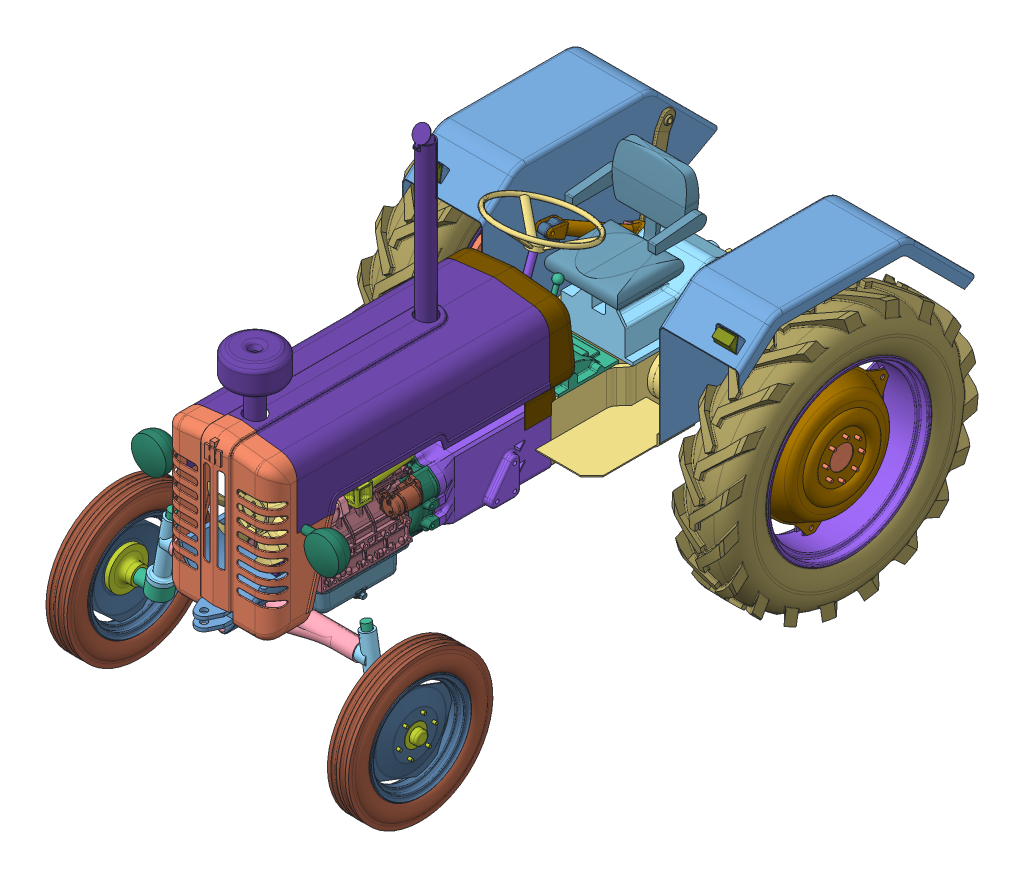
SolidWorks assembly Mc Cormik-D326, configuration Default. Lengths in mm.
Overall size (1708.06 2244.02 3061.96).
66 component instances, 48 part files, 134 mates.
Components (placement in the parent):
- Pivot Axle-1: Pivot Axle [Default] at (-85.0186 771.2904 1627.9761) x (-1 0 0) z (0 0 -1) size (392.24 270 440)
- Rear Hub-1: Rear Hub [Default] at (711.9814 589.2904 -376.0239) x (0 -0.617055 0.78692) z (-1 0 0) size (220 220 100)
- Rear Hub-2: Rear Hub [Default] at (-878.0186 589.2904 -376.0239) x (0 -0.032146 0.999483) z (1 0 0) size (220 220 100)
- Block-1: Block [Default<As Machined>] at (-263.0186 534.2904 273.9761) size (1440 380 1075)
- Coupling-1: Coupling [Default] at (-118.0186 379.2904 -199.5137) size (70 87 710)
- Liftng Block-1: Liftng Block [Default] at (-83.0186 814.2904 -51.0239) size (360 240 555)
- Transmision Cover-1: Transmision Cover [Défaut] at (-73.0186 811.2904 238.9721) size (250 361.14 270)
- Soporte del tiro-1: Soporte del tiro [Default] at (-213.0186 429.2904 -619.0239) size (315 325 60)
- Clutch Block-1: Clutch Block [Default] at (-83.0186 672.7904 708.9761) x (0 0 -1) z (1 0 0) size (619.03 793.15 344.07)
- Lift Arm-1: Lift Arm [Default] at (241.9814 982.0279 -696.6432) x (0 0.10751 -0.994204) z (1 0 0) size (387.95 79.9 190.01)
- Lift Arm-3: Lift Arm [Default] at (-408.0186 1036.5986 -195.6199) x (0 0.319024 0.947747) z (-1 0 0) size (387.95 79.9 190.01)
- Lift Pivot-1: Lift Pivot [Default] at (229.4814 914.6963 -770.8621) x (0 0.061661 -0.998097) z (1 0 0) size (72 95 40)
- Lift Pivot-2: Lift Pivot [Default] at (-355.5186 1024.9831 -196.1551) x (0 0.891699 -0.45263) z (1 0 0) size (72 95 40)
- Lift Rod-1: Lift Rod [Default] at (209.4814 931.3672 -748.7921) x (0 -0.061661 0.998097) z (-0.99998 -0.006262 -0.000387) size (40 357.5 35)
- Lift Rod-2: Lift Rod [Default] at (-375.5186 1051.8561 -189.6097) x (0 0.891699 -0.45263) z (0.99998 -0.00284 -0.005595) size (40 357.5 35)
- Lift LowerArm-1: Lift LowerArm [Default] at (-285.5186 418.635 -395.5257) x (0 0.879068 -0.476697) z (1 0 0) size (846.21 65 187.5)
- Lift LowerArm-2: Lift LowerArm [Default] at (119.4814 500.3905 -344.926) x (0 0.034513 -0.999404) z (-1 0 0) size (846.21 65 187.5)
- Caliper Lift-1: Caliper Lift [Default] at (226.2961 461.8114 -768.9267) x (-0.217519 -0.287281 0.932821) z (-0.057344 0.957815 0.281607) size (69.72 40 130.52)
- Caliper Lift-2: Caliper Lift [Default] at (-403.5766 839.073 -608.497) x (-0.220379 0.743502 -0.631378) z (-0.045125 0.638828 0.768025) size (69.72 40 130.52)
- Seat-1: Seat [Default] at (-57.0186 1084.2904 -121.0239) size (410 504.01 388.87)
- Light Base-1: Light Base [Default] at (-475.0186 971.2904 1563.3117) x (1 0 0) z (0 0 -1) size (220 160 110)
- Light Base-2: Light Base [Default] at (304.9814 971.2904 1563.3117) x (-1 0 0) z (0 0 -1) size (220 160 110)
- Rear Light-1: Rear Light [Default] at (584.9814 1164.398 -2.5754) x (1 0 0) z (0 0.752577 0.658505) size (94.41 53.41 45)
- Rear Light-2: Rear Light [Default] at (-751.0186 1164.398 -2.5754) x (1 0 0) z (0 0.752577 0.658505) size (94.41 53.41 45)
- Hood-1: Hood [Default<As Machined>] at (-85.0186 971.2904 393.3117) x (-1 0 0) z (0 0 -1) size (510 1063.82 1200)
- Dashboard-1: Dashboard [Default] at (-85.0186 749.2904 393.3117) x (0 0 -1) z (1 0 0) size (154.34 530 500)
- MudGuard-1: MudGuard [Default] at (316.9814 659.2904 48.9761) size (360 600 1070)
- MudGuard-4: MudGuard [MirrorDefault] at (-483.0186 659.2904 48.9761) x (-1 0 0) z (0 0 -1) size (360 600 1070)
- Grill-1: Grill [Default] at (-85.0186 561.2904 1643.3117) x (-1 0 0) z (0 0 -1) size (510 729 293)
- Steering Wheel-1: Steering Wheel [Default] at (-83.0186 1303.368 214.0461) x (1 0 0) z (0 0.34202 0.939693) size (420 110 420)
- Axle-1: Axle [Default] at (-85.0186 531.2904 1407.9761) x (0 0 -1) z (1 0 0) size (330 139.57 830)
- Axle Estension-1: Axle Estension [Default] at (379.9814 498.3414 1407.9761) x (0.984808 0.173648 0) z (0 0 1) size (309.72 270 100)
- Axle Estension-2: Axle Estension [Default] at (-550.0186 498.3414 1407.9761) x (-0.984808 0.173648 0) z (0 0 -1) size (309.72 270 100)
- Upright-2: Upright [Default] at (-580.4071 326 1407.9761) x (0 0 1) z (-1 0 0) size (100 368.31 198.74)
- Upright-1: Upright [Default] at (410.3698 326 1407.9761) x (0 0 -1) z (1 0 0) size (100 368.31 198.74)
- Front Hub-1: Front Hub [Default] at (606.3698 326 1407.9761) x (0 0.628717 -0.777634) z (1 0 0) size (180 180 106)
- Front Hub-2: Front Hub [Default] at (-776.4071 326 1407.9761) x (0 0.301517 -0.953461) z (-1 0 0) size (180 180 106)
- Sitting Rim-1: Sitting Rim [Default] at (-806.0186 589.2904 -376.0239) x (0 0.999508 0.03137) z (-1 0 0) size (746 746 224)
- Sitting Rim-2: Sitting Rim [Default] at (639.9814 589.2904 -376.0239) x (0 0.393074 -0.919507) z (1 0 0) size (746 746 224)
- Wheel-2: Wheel [Default] at (706.9814 589.2904 -376.0239) x (0 -0.120113 -0.99276) z (1 0 0) size (592.92 665 128)
- Wheel-1: Wheel [Default] at (-873.0186 589.2904 -376.0239) x (0 0.032146 -0.999483) z (-1 0 0) size (592.92 665 128)
- Front Wheel-1: Front Wheel [Default] at (550.3698 326 1407.9761) x (0 -0.359092 -0.933302) z (-1 0 0) size (457.58 457.58 102)
- Front Wheel-2: Front Wheel [Default] at (-720.4071 326 1407.9761) x (0 -0.674963 -0.737852) z (1 0 0) size (457.58 457.58 102)
- FrontTire-1: FrontTire [Default] at (550.3698 326 1407.9761) x (0 -0.359092 -0.933302) z (0 -0.933302 0.359092) size (652.76 122 652.76)
- FrontTire-3: FrontTire [Default] at (-720.4071 326 1407.9761) x (0 -0.674963 -0.737852) z (0 -0.737852 0.674963) size (652.76 122 652.76)
- Rear Tire-1: Rear Tire [-] at (639.9814 589.2904 -376.0239) x (1 0 0) z (0 -0.919507 -0.393074) size (262.06 1212.92 1215.75)
- Rear Tire-2: Rear Tire [-] at (-806.0186 589.2904 -376.0239) x (1 0 0) z (0 -0.03137 0.999508) size (262.06 1212.92 1215.75)
- v2203_01891-1: v2203_01891 [Default] at (-83.0186 672.7904 1188.4761) x (0 0 -1) z (0.999391 0.034899 0) size (669.39 681.44 494.99)
  - CORE_01891-1: CORE_01891 [Default] at origin size (596.01 515.55 494.99)
  - OILP_01891-1: OILP_01891 [Default] at origin size (410.6 144 247)
  - FWHU_01891-1: FWHU_01891 [Default] at origin size (90.23 313.63 348.46)
  - FLWH_01891-1: FLWH_01891 [Default] at origin size (61 275 275)
  - PUFD_01891-1: PUFD_01891 [Default] at origin size (40.5 104 104)
  - CNUT_01891-1: CNUT_01891 [Default] at origin size (12 53.12 46)
  - FANP_01891-1: FANP_01891 [Default] at origin size (51.6 99 99)
  - FANC_01891-1: FANC_01891 [Default] at origin size (20.01 72.12 72.11)
  - FAN_01891-1: FAN_01891 [Default] at origin size (50.42 403.32 417.06)
  - ALTN_01891-1: ALTN_01891 [Default] at origin size (153.25 171.12 110.56)
  - VBLT_01891-1: VBLT_01891 [Default] at origin size (13.3 332.62 274.79)
  - INMN_01891-1: INMN_01891 [Default] at origin size (386.24 179.55 160.5)
  - EXMN_01891-1: EXMN_01891 [Default] at origin size (355.04 75.17 112.05)
  - TCOV_01891-1: TCOV_01891 [Default] at origin size (74.25 65 58)
  - SPED_01891-1: SPED_01891 [Default] at origin size (61.44 39.2 44.81)
  - STOP_01891-1: STOP_01891 [Default] at origin size (38.48 11.5 85.71)
  - STRT_01891-1: STRT_01891 [Default] at origin size (194.61 148.21 134.43)
  - OILF_01891-1: OILF_01891 [Default] at origin size (97.5 97.5 85.5)
Mates (geometry in assembly coordinates):
- Coincident1: coincident anti-aligned: plane of Block-1 through (96.9814 799.2904 273.9761) normal (0 1 0); plane of Transmision Cover-1 through (51.9814 799.2904 -31.0279) normal (0 -1 0)
- Coincident2: coincident anti-aligned: plane of Block-1 through (96.9814 799.2904 273.9761) normal (0 1 0); plane of Liftng Block-1 through (-233.0186 799.2904 -576.0239) normal (0 -1 0)
- Coincident3: coincident aligned: plane of Block-1 through (96.9814 243.0787 -46.0239) normal (1 0 0); plane of Liftng Block-1 through (96.9814 799.2904 -51.0239) normal (1 0 0)
- Coincident5: coincident anti-aligned: plane of Block-1 through (96.9814 799.2904 273.9761) normal (0 1 0); plane of Transmision Cover-1 through (51.9814 799.2904 -31.0279) normal (0 -1 0)
- Coincident6: coincident aligned: plane of Block-1 through (51.9814 419.2894 273.9761) normal (1 0 0); plane of Transmision Cover-1 through (51.9814 799.2904 238.9721) normal (1 0 0)
- Coincident7: coincident anti-aligned: plane of Liftng Block-1; plane of Transmision Cover-1
- Concentric1: concentric anti-aligned: cylinder of Block-1 through (-83.0186 574.2904 -631.0239) axis (0 0 1) radius 55; cylinder of Soporte del tiro-1 through (-83.0186 574.2904 -611.0239) axis (0 0 -1) radius 60
- Coincident11: coincident anti-aligned: plane of Block-1 through (-579.8311 799.2904 -611.0239) normal (0 0 -1); plane of Soporte del tiro-1 through (-213.0186 429.2904 -611.0239) normal (0 0 1)
- Parallel1: parallel anti-aligned: plane of Block-1 through (41.9814 689.2904 -611.0239) normal (0 -1 0); plane of Soporte del tiro-1 through (46.9814 684.2904 -611.0239) normal (0 1 0)
- Coincident12: coincident anti-aligned: plane of Coupling-1 through (-48.0186 379.2904 -1111.036) normal (0 -1 0); plane of Soporte del tiro-1 through (-118.0186 379.2904 -671.0239) normal (0 1 0)
- Coincident13: coincident anti-aligned: plane of Coupling-1 through (-118.0186 422.7904 -1111.036) normal (-1 0 0); plane of Soporte del tiro-1 through (-118.0186 379.2904 -671.0239) normal (1 0 0)
- Tangent1: tangent anti-aligned: cylinder of Block-1 through (96.9814 659.8786 -376.0239) axis (-1 0 0) radius 240.5882; cylinder of Coupling-1 through (-48.0186 421.2904 -271.2294) axis (-1 0 0) radius 20
- Coincident19: coincident anti-aligned: plane of Block-1 through (-803.0186 659.2904 -331.0239) normal (0 1 0); plane of MudGuard-4 through (-843.0186 659.2904 48.9761) normal (0 -1 0)
- Coincident20: coincident aligned: plane of Block-1 through (-483.0186 858.539 -471.0239) normal (1 0 0); plane of MudGuard-4 through (-483.0186 1543.9571 -436.3572) normal (1 0 0)
- Coincident21: coincident aligned: plane of Block-1 through (-483.0186 858.539 -281.0239) normal (0 0 1); plane of MudGuard-4 through (-543.0186 659.2904 -281.0239) normal (0 0 1)
- Coincident22: coincident anti-aligned: plane of Block-1 through (636.9814 659.2904 -331.0239) normal (0 1 0); plane of MudGuard-1 through (676.9814 659.2904 48.9761) normal (0 -1 0)
- Coincident23: coincident aligned: plane of Block-1 through (316.9814 858.539 -471.0239) normal (-1 0 0); plane of MudGuard-1 through (316.9814 1543.9571 -436.3572) normal (-1 0 0)
- Coincident24: coincident aligned: plane of Block-1 through (316.9814 858.539 -281.0239) normal (0 0 1); plane of MudGuard-1 through (376.9814 659.2904 -281.0239) normal (0 0 1)
- Concentric2: concentric aligned: cylinder of Liftng Block-1 through (-228.0186 954.2904 -440.1385) axis (1 0 0) radius 15; cylinder of Lift Arm-1 through (51.9814 954.2904 -440.1385) axis (1 0 0) radius 15
- Coincident26: coincident anti-aligned: plane of Liftng Block-1 through (61.9814 954.2904 -440.1385) normal (1 0 0); plane of Lift Arm-1 through (61.9814 954.2904 -440.1385) normal (-1 0 0)
- Coincident27: coincident anti-aligned: plane of Liftng Block-1 through (-228.0186 954.2904 -440.1385) normal (-1 0 0); plane of Lift Arm-3 through (-228.0186 954.2904 -440.1385) normal (1 0 0)
- Concentric3: concentric anti-aligned: cylinder of Liftng Block-1 through (-228.0186 954.2904 -440.1385) axis (1 0 0) radius 15; cylinder of Lift Arm-3 through (-218.0186 954.2904 -440.1385) axis (-1 0 0) radius 15
- Concentric4: concentric anti-aligned: cylinder of Lift Arm-1 through (176.9814 989.5536 -766.2375) axis (1 0 0) radius 7.5; cylinder of Lift Pivot-1 through (229.4814 989.5536 -766.2375) axis (-1 0 0) radius 7.5
- Coincident28: coincident anti-aligned: plane of Lift Arm-1 through (189.4814 961.8767 -789.3469) normal (1 0 0); plane of Lift Pivot-1 through (189.4814 954.8553 -788.4192) normal (-1 0 0)
- Concentric5: concentric aligned: cylinder of Lift Arm-3 through (-343.0186 1058.9303 -129.2777) axis (-1 0 0) radius 7.5; cylinder of Lift Pivot-2 through (-355.5186 1058.9303 -129.2777) axis (-1 0 0) radius 7.5
- Coincident29: coincident anti-aligned: plane of Lift Arm-3 through (-395.5186 1036.8775 -100.7517) normal (1 0 0); plane of Lift Pivot-2 through (-395.5186 1060.4696 -170.4314) normal (-1 0 0)
- Concentric6: concentric anti-aligned: cylinder of Lift Pivot-1 through (209.4814 930.4422 -733.8207) axis (0 0.061661 -0.998097) radius 7.5; cylinder of Lift Rod-1 through (209.4814 933.8336 -788.716) axis (0 -0.061661 0.998097) radius 7.5
- Coincident30: coincident anti-aligned: plane of Lift Pivot-1 through (189.4814 913.4014 -749.902) normal (0 0.061661 -0.998097); plane of Lift Rod-1 through (209.4814 931.3672 -748.7921) normal (0 -0.061661 0.998097)
- Concentric7: concentric aligned: cylinder of Lift Pivot-2 through (-375.5186 1001.0293 -163.8098) axis (0 0.891699 -0.45263) radius 7.5; cylinder of Lift Rod-2 through (-375.5186 1016.1882 -171.5045) axis (0 0.891699 -0.45263) radius 7.5
- Coincident31: coincident anti-aligned: plane of Lift Pivot-2 through (-395.5186 1061.814 -169.9923) normal (0 -0.891699 0.45263); plane of Lift Rod-2 through (-375.5186 1051.8561 -189.6097) normal (0 0.891699 -0.45263)
- Concentric8: concentric anti-aligned: cylinder of Block-1 through (-358.0186 469.2904 -386.0239) axis (1 0 0) radius 10; cylinder of Lift LowerArm-1 through (-285.5186 469.2904 -386.0239) axis (-1 0 0) radius 10
- Coincident32: coincident anti-aligned: plane of Block-1 through (-278.0186 484.2904 -326.0239) normal (-1 0 0); plane of Lift LowerArm-1 through (-278.0186 460.4997 -381.2569) normal (1 0 0)
- Concentric9: concentric anti-aligned: cylinder of Block-1 through (191.9814 469.2904 -386.0239) axis (-1 0 0) radius 10; cylinder of Lift LowerArm-2 through (119.4814 469.2904 -386.0239) axis (1 0 0) radius 10
- Coincident33: coincident anti-aligned: plane of Block-1 through (111.9814 484.2904 -326.0239) normal (1 0 0); plane of Lift LowerArm-2 through (111.9814 468.9453 -376.0298) normal (-1 0 0)
- Coincident34: coincident anti-aligned: plane of Lift LowerArm-2 through (119.4814 438.2593 -429.1205) normal (-0.97437 0.007764 -0.224817); plane of Caliper Lift-1 through (210.1794 554.9264 -818.1822) normal (0.97437 -0.007764 0.224817)
- Concentric10: concentric aligned: cylinder of Lift Rod-1 through (209.3715 950.0677 -767.6749) axis (0.006274 -0.998077 -0.06166) radius 10; cylinder of Caliper Lift-1 through (211.6146 593.254 -789.7185) axis (0.006274 -0.998077 -0.06166) radius 10
- Coincident35: coincident anti-aligned: plane of Lift Rod-1 through (211.6146 593.254 -789.7185) normal (0.006274 -0.998077 -0.06166); plane of Caliper Lift-1 through (211.6146 593.254 -789.7185) normal (-0.006274 0.998077 0.06166)
- Concentric11: concentric aligned: cylinder of Lift LowerArm-2 through (393.8629 482.0189 -754.6101) axis (-0.97437 0.007764 -0.224817) radius 10; cylinder of Caliper Lift-1 through (231.7922 483.3102 -792.0047) axis (-0.97437 0.007764 -0.224817) radius 10
- Coincident36: coincident anti-aligned: plane of Lift LowerArm-1 through (-285.5186 521.7039 -377.4754) normal (0.97437 0.197747 -0.107233); plane of Caliper Lift-2 through (-364.9735 841.7719 -509.2057) normal (-0.97437 -0.197747 0.107233)
- Concentric12: concentric aligned: cylinder of Lift Rod-2 through (-375.4088 1041.9435 -164.9518) axis (-0.006274 -0.452621 -0.891681) radius 10; cylinder of Caliper Lift-2 through (-377.6519 880.1311 -483.7287) axis (-0.006274 -0.452621 -0.891681) radius 10
- Coincident37: coincident anti-aligned: plane of Lift Rod-2 through (-377.6519 880.1311 -483.7287) normal (-0.006274 -0.452621 -0.891681); plane of Caliper Lift-2 through (-377.6519 880.1311 -483.7287) normal (0.006274 0.452621 0.891681)
- Concentric13: concentric aligned: cylinder of Lift LowerArm-1 through (-559.9002 793.4958 -561.8324) axis (0.97437 0.197747 -0.107233) radius 10; cylinder of Caliper Lift-2 through (-397.8295 826.3879 -579.6689) axis (0.97437 0.197747 -0.107233) radius 10
- Coincident44: coincident anti-aligned: plane of Hood-1 through (-253.0186 1176.5421 1533.3117) normal (0 0 1); plane of Grill-1 through (-335.0186 118.558 1533.3117) normal (0 0 -1)
- Coincident45: coincident anti-aligned: plane of Hood-1 through (164.9814 971.2904 1533.3117) normal (0 -1 0); plane of Grill-1 through (-335.0186 971.2904 1703.1285) normal (0 1 0)
- Coincident46: coincident aligned: plane of Hood-1 through (-335.0186 971.2904 1533.3117) normal (-1 0 0); plane of Grill-1 through (-335.0186 561.2904 1373.3117) normal (-1 0 0)
- Coincident47: coincident aligned: plane of Hood-1 through (-335.0186 971.2904 1533.3117) normal (-1 0 0); plane of Dashboard-1 through (-335.0186 1249.2904 233.3117) normal (-1 0 0)
- Coincident52: coincident anti-aligned: plane of Block-1 through (51.9814 419.2894 273.9761) normal (1 0 0); plane of Dashboard-1 through (51.9814 749.2904 233.3117) normal (-1 0 0)
- Coincident53: coincident: plane of Transmision Cover-1 through (-198.0186 799.2904 238.9721) normal (0 0 1); line of Dashboard-1 through (24.9814 799.2904 238.9721) axis (-1 0 0)
- Coincident55: coincident anti-aligned: plane of Grill-1 through (-462.0724 631.2904 1373.3107) normal (0 -1 0); plane of Pivot Axle-1 through (-85.0186 631.2904 1702.9761) normal (0 1 0)
- Coincident56: coincident: line of Grill-1 through (-85.0186 1188.2904 1662.3117) axis (0 -1 0); plane of Pivot Axle-1 through (-85.0186 771.2904 1627.9761) normal (-1 0 0)
- Concentric14: concentric aligned: cylinder of Block-1 through (-264.7107 589.2904 -376.0239) axis (1 0 0) radius 30; cylinder of Rear Hub-1 through (636.9814 589.2904 -376.0239) axis (1 0 0) radius 30
- Coincident57: coincident anti-aligned: plane of Rear Hub-1 through (636.9814 570.7787 -352.4163) normal (-1 0 0); plane of Block-1 through (636.9814 544.2904 -331.0239) normal (1 0 0)
- Concentric15: concentric aligned: cylinder of Block-1 through (98.6734 589.2904 -376.0239) axis (-1 0 0) radius 30; cylinder of Rear Hub-2 through (-803.0186 589.2904 -376.0239) axis (-1 0 0) radius 30
- Coincident58: coincident anti-aligned: plane of Block-1 through (-803.0186 544.2904 -331.0239) normal (-1 0 0); plane of Rear Hub-2 through (-803.0186 588.326 -346.0394) normal (1 0 0)
- Concentric17: concentric aligned: cylinder of Axle Estension-1 through (403.4239 365.3923 1407.9761) axis (0.173648 -0.984808 0) radius 20; cylinder of Upright-1 through (351.3294 660.8346 1407.9761) axis (0.173648 -0.984808 0) radius 20
- Coincident60: coincident anti-aligned: plane of Axle Estension-1 through (423.12 368.8653 1407.9761) normal (0.173648 -0.984808 0); plane of Upright-1 through (403.4239 365.3923 1407.9761) normal (-0.173648 0.984808 0)
- Parallel3: parallel anti-aligned: cylinder of Upright-1 through (530.3698 326 1407.9761) axis (-1 0 0) radius 30; cylinder of Upright-2 through (-700.4071 326 1407.9761) axis (1 0 0) radius 30
- Concentric19: concentric aligned: cylinder of Upright-1 through (530.3698 326 1407.9761) axis (-1 0 0) radius 30; cylinder of Front Hub-1 through (606.3698 326 1407.9761) axis (-1 0 0) radius 30
- Coincident62: coincident anti-aligned: plane of Front Hub-1 through (530.3698 326 1407.9761) normal (-1 0 0); plane of Upright-1 through (530.3698 326 1407.9761) normal (1 0 0)
- Concentric21: concentric anti-aligned: cylinder of Pivot Axle-1 through (-85.0186 531.2904 1297.9761) axis (0 0 1) radius 20; cylinder of Axle-1 through (-85.0186 531.2904 1764.5447) axis (0 0 -1) radius 20
- Coincident63: coincident anti-aligned: plane of Pivot Axle-1 through (-85.0186 813.2904 1547.9761) normal (0 0 -1); plane of Axle-1 through (-85.0186 531.2904 1547.9761) normal (0 0 1)
- Concentric22: concentric anti-aligned: cylinder of Axle Estension-1 through (116.6156 531.2904 1407.9761) axis (1 0 0) radius 35; cylinder of Axle-1 through (329.9814 531.2904 1407.9761) axis (-1 0 0) radius 35
- Parallel4: parallel anti-aligned: plane of Pivot Axle-1 through (19.7478 631.2904 1367.9761) normal (0 -1 0); plane of Axle-1 through (-99.3552 543.7904 1527.4953) normal (0 1 0)
- Distance1: distance = 50 mm aligned: plane of Axle Estension-1 through (379.9814 531.2904 1407.9761) normal (1 0 0); plane of Axle-1 through (329.9814 531.2904 1407.9761) normal (1 0 0)
- Coincident65: coincident aligned: plane of Upright-1 through (410.3698 326 1407.9761) normal (0 0 -1); plane of Axle-1 through (-85.0186 531.2904 1407.9761) normal (0 0 -1)
- Concentric23: concentric aligned: cylinder of Upright-2 through (-700.4071 326 1407.9761) axis (1 0 0) radius 30; cylinder of Front Hub-2 through (-776.4071 326 1407.9761) axis (1 0 0) radius 30
- Coincident66: coincident anti-aligned: plane of Upright-2 through (-700.4071 326 1407.9761) normal (-1 0 0); plane of Front Hub-2 through (-700.4071 326 1407.9761) normal (1 0 0)
- Concentric24: concentric aligned: cylinder of Upright-2 through (-521.3667 660.8346 1407.9761) axis (-0.173648 -0.984808 0) radius 20; cylinder of Axle Estension-2 through (-573.4611 365.3923 1407.9761) axis (-0.173648 -0.984808 0) radius 20
- Coincident67: coincident anti-aligned: plane of Upright-2 through (-573.4611 365.3923 1407.9761) normal (0.173648 0.984808 0); plane of Axle Estension-2 through (-593.1573 368.8653 1407.9761) normal (-0.173648 -0.984808 0)
- Concentric26: concentric aligned: cylinder of Axle-1 through (329.9814 531.2904 1407.9761) axis (-1 0 0) radius 35; cylinder of Axle Estension-2 through (-286.6529 531.2904 1407.9761) axis (-1 0 0) radius 35
- Distance2: distance = 50 mm aligned: plane of Axle-1 through (-500.0186 531.2904 1407.9761) normal (-1 0 0); plane of Axle Estension-2 through (-550.0186 531.2904 1407.9761) normal (-1 0 0)
- Coincident69: coincident anti-aligned: plane of Axle-1 through (-85.0186 531.2904 1407.9761) normal (0 0 -1); plane of Upright-2 through (-580.4071 326 1407.9761) normal (0 0 1)
- Concentric30: concentric anti-aligned: cylinder of Wheel-1 through (-881.0186 586.6705 -294.566) axis (-1 0 0) radius 7.5; cylinder of Rear Hub-2 through (-903.0186 586.6705 -294.566) axis (1 0 0) radius 7
- Coincident72: coincident anti-aligned: plane of Rear Hub-2 through (-873.0186 587.5867 -323.0513) normal (-1 0 0); plane of Wheel-1 through (-873.0186 592.999 -491.3303) normal (1 0 0)
- Coincident73: coincident anti-aligned: plane of Wheel-1 through (-773.0186 599.979 -708.352) normal (1 0 0); plane of Sitting Rim-1 through (-773.0186 725.5749 -68.979) normal (-1 0 0)
- Concentric33: concentric aligned: circle of Wheel-1; cylinder of Sitting Rim-1 through (-703.4189 589.2904 -376.0239) axis (1 0 0) radius 335
- Concentric34: concentric anti-aligned: cylinder of Wheel-1 through (-901.0186 735.556 -103.2663) axis (1 0 0) radius 10; cylinder of Sitting Rim-1 through (-694.0186 735.556 -103.2663) axis (-1 0 0) radius 10
- Concentric35: concentric aligned: circle of Wheel-2; cylinder of Sitting Rim-2 through (537.3816 589.2904 -376.0239) axis (-1 0 0) radius 335
- Coincident74: coincident anti-aligned: plane of Wheel-2 through (606.9814 549.353 -706.1167) normal (-1 0 0); plane of Sitting Rim-2 through (606.9814 697.9825 -693.8855) normal (1 0 0)
- Concentric36: concentric anti-aligned: cylinder of Wheel-2 through (734.9814 403.6586 -623.6751) axis (-1 0 0) radius 10; cylinder of Sitting Rim-2 through (527.9814 403.6586 -623.6751) axis (1 0 0) radius 10
- Concentric37: concentric anti-aligned: cylinder of Wheel-2 through (706.9814 589.2904 -376.0239) axis (-1 0 0) radius 53; cylinder of Rear Hub-1 through (636.9814 589.2904 -376.0239) axis (1 0 0) radius 110
- Coincident75: coincident anti-aligned: plane of Rear Hub-1 through (706.9814 556.5865 -334.3171) normal (1 0 0); plane of Wheel-2 through (706.9814 575.4335 -490.5547) normal (-1 0 0)
- Coincident77: coincident anti-aligned: circle of Rear Hub-2; cylinder of Wheel-1 through (-873.0186 589.2904 -376.0239) axis (1 0 0) radius 53
- Concentric42: concentric anti-aligned: cylinder of Rear Hub-1 through (736.9814 525.1564 -426.3139) axis (-1 0 0) radius 7; cylinder of Wheel-2 through (714.9814 525.1564 -426.3139) axis (1 0 0) radius 7.5
- Coincident78: coincident anti-aligned: plane of Front Hub-1 through (570.3698 382.5846 1337.9891) normal (1 0 0); plane of Front Wheel-1 through (570.3698 186.9378 1461.4809) normal (-1 0 0)
- Concentric43: concentric aligned: cylinder of Front Hub-1 through (606.3698 326 1407.9761) axis (-1 0 0) radius 30; cylinder of Front Wheel-1 through (486.8345 326 1407.9761) axis (-1 0 0) radius 50
- Concentric44: concentric aligned: cylinder of Front Hub-1 through (590.3698 249.9359 1437.2421) axis (-1 0 0) radius 6.5; cylinder of Front Wheel-1 through (570.3698 249.9359 1437.2421) axis (-1 0 0) radius 6.5
- Coincident79: coincident anti-aligned: plane of Front Hub-2 through (-740.4071 353.1365 1322.1647) normal (-1 0 0); plane of Front Wheel-2 through (-740.4071 435.9401 1307.4065) normal (1 0 0)
- Concentric45: concentric aligned: cylinder of Front Hub-2 through (-776.4071 326 1407.9761) axis (1 0 0) radius 30; cylinder of Front Wheel-2 through (-656.8718 326 1407.9761) axis (1 0 0) radius 50
- Concentric46: concentric aligned: cylinder of Front Hub-2 through (-760.4071 386.1349 1352.9667) axis (1 0 0) radius 6.5; cylinder of Front Wheel-2 through (-740.4071 386.1349 1352.9667) axis (1 0 0) radius 6.5
- Concentric47: concentric anti-aligned: cylinder of Front Wheel-1 through (486.8345 326 1407.9761) axis (-1 0 0) radius 208; cylinder of FrontTire-1 through (519.3698 326 1407.9761) axis (1 0 0) radius 208
- Concentric48: concentric aligned: cylinder of Front Wheel-2 through (-656.8718 326 1407.9761) axis (1 0 0) radius 193; cylinder of FrontTire-3 through (-751.4071 326 1407.9761) axis (1 0 0) radius 208
- Coincident81: coincident anti-aligned: plane of Front Wheel-2 through (-683.4071 435.9401 1307.4065) normal (-1 0 0); plane of FrontTire-3 through (-683.4071 185.6078 1254.5029) normal (1 0 0)
- Concentric49: concentric aligned: cylinder of Sitting Rim-2 through (537.3816 589.2904 -376.0239) axis (-1 0 0) radius 340; cylinder of Rear Tire-1 through (424.8282 589.2904 -376.0239) axis (-1 0 0) radius 360
- Coincident83: coincident anti-aligned: plane of Sitting Rim-2 through (534.9814 377.3538 119.7536) normal (1 0 0); plane of Rear Tire-1 through (534.9814 443.8531 -35.8063) normal (-1 0 0)
- Concentric50: concentric anti-aligned: cylinder of Sitting Rim-1 through (-703.4189 589.2904 -376.0239) axis (1 0 0) radius 340; cylinder of Rear Tire-2 through (-1021.1718 589.2904 -376.0239) axis (-1 0 0) radius 360
- Coincident84: coincident anti-aligned: plane of Sitting Rim-1 through (-911.0186 50.3783 -392.9379) normal (1 0 0); plane of Rear Tire-2 through (-911.0186 959.1083 -364.417) normal (-1 0 0)
- Coincident91: coincident anti-aligned: line of Hood-1 through (-85.0186 1279.2904 629.8142) axis (0 0 -1); line of Dashboard-1 through (-85.0186 1279.2904 320.1313) axis (0 0 1)
- Coincident92: coincident anti-aligned: plane of Hood-1 through (-253.0186 1176.5421 393.3117) normal (0 0 -1); plane of Dashboard-1 through (-225.0186 749.2904 393.3117) normal (0 0 1)
- Coincident93: coincident anti-aligned: plane of Front Wheel-1 through (587.3698 186.9378 1461.4809) normal (-1 0 0); plane of FrontTire-1 through (587.3698 251.3088 1213.8493) normal (1 0 0)
- Coincident94: coincident anti-aligned: plane of Block-1 through (96.9814 799.2904 273.9761) normal (0 1 0); plane of Dashboard-1 through (54.9814 799.2904 273.9761) normal (0 -1 0)
- Coincident95: coincident anti-aligned: plane of MudGuard-1 through (542.9814 1100.6363 -93.5792) normal (0 -0.658505 0.752577); plane of Rear Light-1 through (542.9814 1185.6112 -19.2261) normal (0 0.658505 -0.752577)
- Coincident96: coincident anti-aligned: plane of MudGuard-1 through (631.9814 1097.3438 -89.8163) normal (-1 0 0); plane of Rear Light-1 through (631.9814 1154.003 16.8975) normal (1 0 0)
- Coincident97: coincident anti-aligned: plane of MudGuard-1 through (676.9814 1259.2904 -111.0239) normal (0 0.752577 0.658505); plane of Rear Light-1 through (626.9814 1150.2401 13.605) normal (0 -0.752577 -0.658505)
- Coincident98: coincident anti-aligned: plane of MudGuard-4 through (-709.0186 1100.6363 -93.5792) normal (0 -0.658505 0.752577); plane of Rear Light-2 through (-793.0186 1185.6112 -19.2261) normal (0 0.658505 -0.752577)
- Coincident99: coincident anti-aligned: plane of MudGuard-4 through (-704.0186 1065.7355 -53.6926) normal (-1 0 0); plane of Rear Light-2 through (-704.0186 1154.003 16.8975) normal (1 0 0)
- Coincident100: coincident anti-aligned: plane of MudGuard-4 through (-843.0186 1259.2904 -111.0239) normal (0 0.752577 0.658505); plane of Rear Light-2 through (-709.0186 1150.2401 13.605) normal (0 -0.752577 -0.658505)
- Coincident105: coincident aligned: plane of Block-1 through (96.9814 799.2904 -606.0239) normal (0 0 -1); plane of Liftng Block-1 through (66.9814 799.2904 -606.0239) normal (0 0 -1)
- Coincident106: coincident anti-aligned: plane of Block-1 through (96.9814 534.2904 273.9761) normal (0 0 1); plane of Dashboard-1 through (-225.0186 799.2904 273.9761) normal (0 0 -1)
- Coincident107: coincident anti-aligned: plane of Sitting Rim-2; plane of Rear Tire-1 through (639.9814 589.2904 -376.0239) normal (0 -0.393074 0.919507)
- Coincident108: coincident aligned: plane of Sitting Rim-1; plane of Rear Tire-2 through (-806.0186 589.2904 -376.0239) normal (0 0.999508 0.03137)
- GearMate1: gear = 670 : 670 mm: cylinder of Sitting Rim-2 through (537.3816 589.2904 -376.0239) axis (-1 0 0) radius 335; cylinder of Sitting Rim-1 through (-703.4189 589.2904 -376.0239) axis (1 0 0) radius 335
- Coincident109: coincident aligned: plane of Front Wheel-1; plane of FrontTire-1
- Coincident110: coincident aligned: plane of Front Wheel-2; plane of FrontTire-3
- Coincident111: coincident aligned: plane of Clutch Block-1 through (-83.0186 1303.368 214.0461) normal (0 0.939693 -0.34202); circle of Steering Wheel-1
- Concentric51: concentric anti-aligned: cylinder of Clutch Block-1 through (-83.0186 1303.368 214.0461) axis (0 -0.939693 0.34202) radius 15; cylinder of Steering Wheel-1 through (-83.0186 1322.1619 207.2057) axis (0 0.939693 -0.34202) radius 35
- Coincident114: coincident anti-aligned: plane of Liftng Block-1 through (-26.0186 1019.2904 -71.0239) normal (-1 0 0); plane of Seat-1 through (-26.0186 1054.2904 -151.0239) normal (1 0 0)
- Coincident115: coincident anti-aligned: plane of Liftng Block-1 through (-228.0186 934.2904 -51.0239) normal (0 1 0); plane of Seat-1 through (-26.0186 934.2904 -131.0239) normal (0 -1 0)
- Coincident116: coincident aligned: plane of Liftng Block-1 through (-228.0186 814.2904 -51.0239) normal (0 0 1); plane of Seat-1 through (-26.0186 1054.2904 -51.0239) normal (0 0 1)
- Coincident117: coincident anti-aligned: plane of Hood-1 through (-335.0186 971.2904 1533.3117) normal (-1 0 0); plane of Light Base-1 through (-335.0186 971.2904 1498.3117) normal (1 0 0)
- Distance3: distance = 80 mm anti-aligned: plane of Light Base-1 through (-475.0186 971.2904 1563.3117) normal (0 0 -1); plane of Grill-1 through (164.9814 561.2904 1643.3117) normal (0 0 1)
- Coincident121: coincident: line of Grill-1 through (-335.0186 971.2904 1396.5215) axis (0 0 1); plane of Light Base-1 through (-475.0186 971.2904 1563.3117) normal (0 -1 0)
- Coincident122: coincident anti-aligned: plane of Grill-1 through (164.9814 1249.2904 1373.3117) normal (1 0 0); plane of Light Base-2 through (164.9814 971.2904 1498.3117) normal (-1 0 0)
- Distance4: distance = 80 mm anti-aligned: plane of Light Base-2 through (304.9814 971.2904 1563.3117) normal (0 0 -1); plane of Grill-1 through (164.9814 561.2904 1643.3117) normal (0 0 1)
- Coincident123: coincident: line of Grill-1 through (-335.0186 971.2904 1396.5215) axis (0 0 1); plane of Light Base-2
- Coincident124: coincident aligned: plane of Clutch Block-1 through (-109.3609 -46.6615 1144.1778) normal (0 -1 0); plane of v2203_01891-1/OILP_01891-1 through (-267.6419 -46.6615 1118.6778) normal (0 -1 0)
- Coincident126: coincident aligned: plane of Pivot Axle-1 through (-85.0186 531.2904 1297.9761) normal (0 0 -1); plane of v2203_01891-1/CORE_01891-1 through (-83.0186 672.7904 1297.9761) normal (0 0 -1)
- Coincident131: coincident aligned: plane of Transmision Cover-1 through (51.9814 811.2904 -31.0279) normal (0 1 0); plane of Clutch Block-1 through (-218.0186 811.2904 273.9761) normal (0 1 0)
- Coincident132: coincident anti-aligned: plane of Block-1 through (96.9814 534.2904 273.9761) normal (0 0 1); plane of Clutch Block-1 through (-218.0186 811.2904 273.9761) normal (0 0 -1)
- Coincident133: coincident aligned: plane of Block-1 through (51.9814 419.2894 273.9761) normal (1 0 0); plane of Clutch Block-1 through (51.9814 534.2904 273.9761) normal (1 0 0)
- Concentric52: concentric aligned: cylinder of Clutch Block-1 through (43.0333 752.2379 818.9761) axis (0 0 -1) radius 53.0076; cylinder of v2203_01891-1/FWHU_01891-1 through (43.0333 752.2379 888.9761) axis (0 0 -1) radius 47
- Coincident135: coincident aligned: plane of Clutch Block-1 through (76.9248 677.043 818.9761) normal (0 0 1); plane of v2203_01891-1/FWHU_01891-1 through (-83.0186 672.7904 818.9761) normal (0 0 1)
- Parallel11: parallel anti-aligned: plane of Block-1 through (96.9814 534.2904 273.9761) normal (0 -1 0); plane of assembly through (0 0 0) normal (0 1 0)
- Tangent6: tangent anti-aligned: cylinder of FrontTire-1 through (519.3698 326 1407.9761) axis (1 0 0) radius 326; plane of assembly through (0 0 0) normal (0 1 0)
